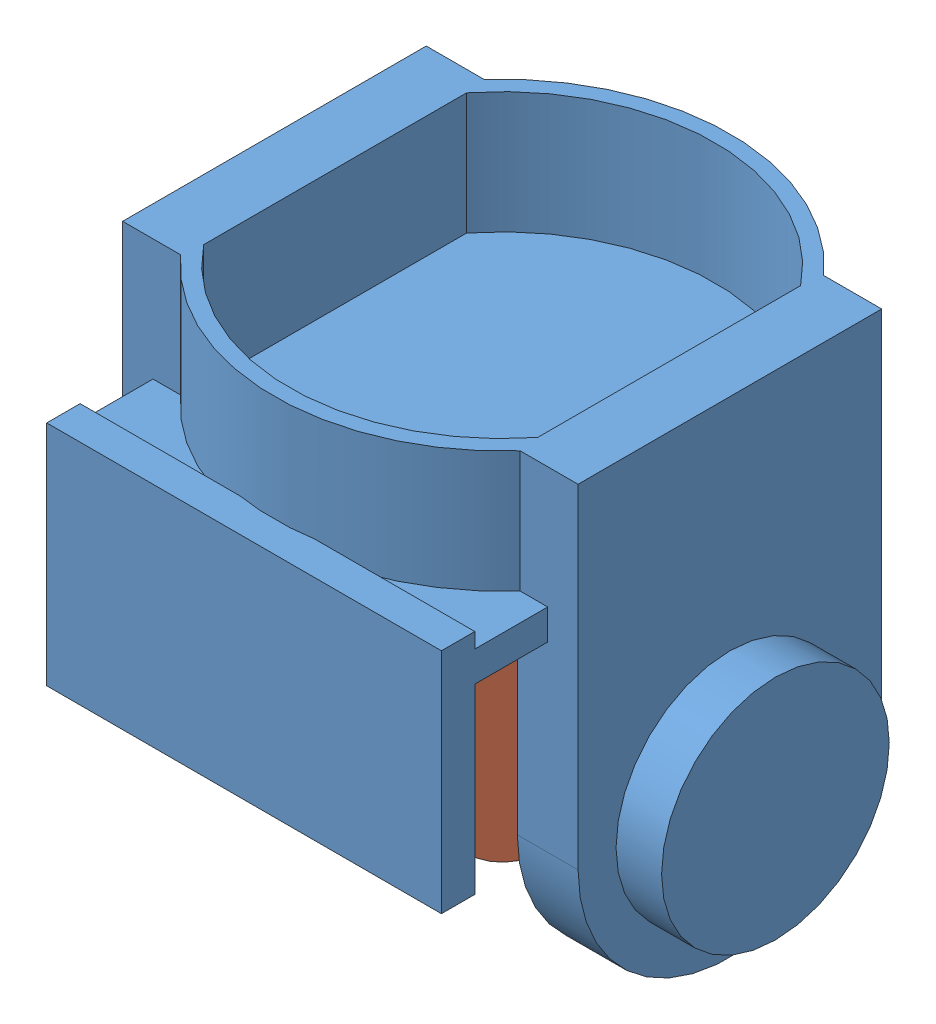
SolidWorks assembly Assem1, configuration Default. Lengths in mm.
Overall size (180 160 160).
2 component instances, 2 part files, 2 mates.
Components (placement in the parent):
- J1-1: J1 [Default] at (110.4372 95.0237 129.9851) size (180 160 160)
- J1_gears-1: J1_gears [Default] at (110.4372 35.0237 129.9851) x (0 0 1) z (-1 0 0) size (90 90 40)
Mates (geometry in assembly coordinates):
- Concentric2: concentric: circle of J1-1; circle of J1_gears-1
- Distance1: distance = 35 mm anti-aligned: plane of J1_gears-1 through (130.4372 35.0237 129.9851) normal (1 0 0); plane of J1-1 through (165.4372 35.0237 79.9851) normal (-1 0 0)
